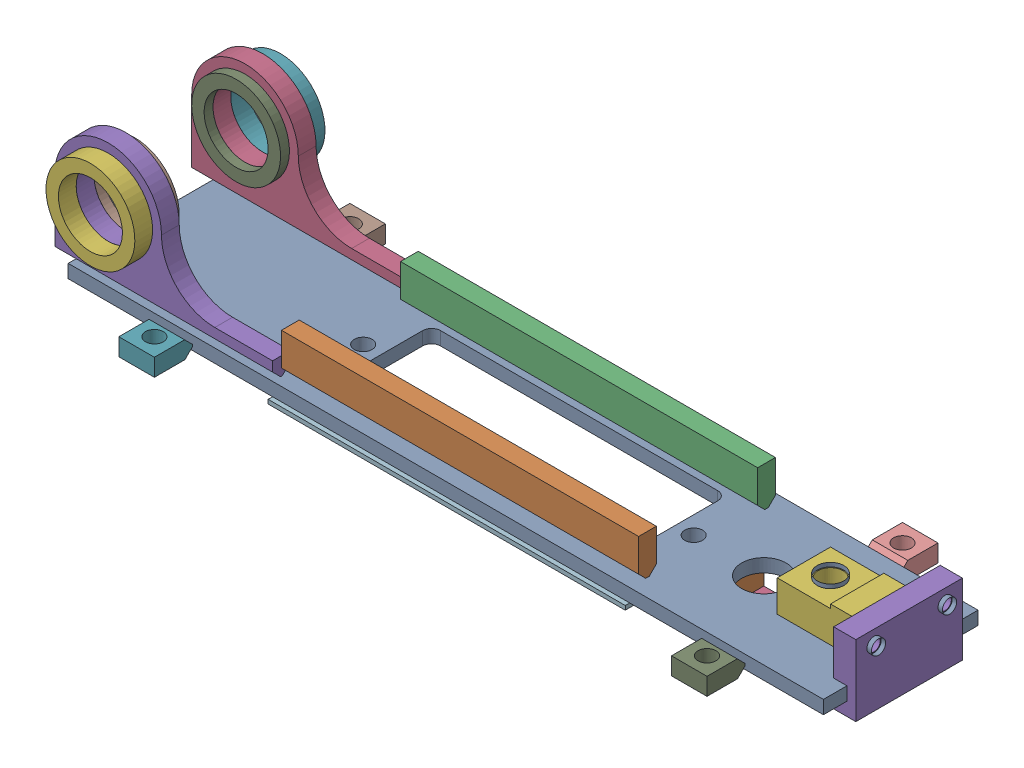
SolidWorks assembly g1_3_1_1_6, configuration 默认. Lengths in mm.
Overall size (880 200 260).
23 component instances, 19 part files, 0 mates.
Components (placement in the parent):
- g1_3_1_1_6-4_af0-1: g1_3_1_1_6-4_af0 [默认] at origin size (850 15 174)
- g1_3_1_1_6-8-1: g1_3_1_1_6-8 [默认] at (0 40 57) x (1 0 0) z (0 -1 0) size (402 20 44.8)
- g1_3_1_1_6-8-2: g1_3_1_1_6-8 [默认] at (0 40 -77) x (1 0 0) z (0 -1 0) size (402 20 44.8)
- g1_3_1_1_6-1-1: g1_3_1_1_6-1 [默认] at (-386 95 -87) x (1 0 0) z (0 -1 0) size (245 20 140)
- g1_3_1_1_6-1-2: g1_3_1_1_6-1 [默认] at (-386 95 67) x (1 0 0) z (0 -1 0) size (245 20 140)
- g1_3_1_1_6-3-1: g1_3_1_1_6-3 [默认] at (-386 95 87) x (-1 0 0) z (0 1 0) size (100 20 100)
- g1_3_1_1_6-3-2: g1_3_1_1_6-3 [默认] at (-386 95 -107) x (-1 0 0) z (0 1 0) size (100 20 100)
- g1_3_1_1_6-2-1: g1_3_1_1_6-2 [默认] at (-386 95 57) x (-1 0 0) z (0 1 0) size (100 10 100)
- g1_3_1_1_6-2-2: g1_3_1_1_6-2 [默认] at (-386 95 -57) x (1 0 0) z (0 1 0) size (100 10 100)
- g1_3_1_1_6-6_af1-1: g1_3_1_1_6-6_af1 [默认] at (186 -5 0) x (0 0 -1) z (1 0 0) size (130 4.6 30)
- g1_3_1_1_6-6_af0-1: g1_3_1_1_6-6_af0 [默认] at (-186 -5 0) x (0 0 -1) z (1 0 0) size (130 4.6 30)
- g1_3_1_1_6-7_af0-1: g1_3_1_1_6-7_af0 [默认] at (0 0 78.5) x (1 0 0) z (0 0 -1) size (402 4.6 27)
- g1_3_1_1_6-7_af1-1: g1_3_1_1_6-7_af1 [默认] at (0 -5 -78.5) size (402 4.6 27)
- g1_3_1_1_6-9-1: g1_3_1_1_6-9 [默认] at (220 -17 0) x (0 1 0) z (0 0 -1) size (35 15 60)
- g1_3_1_1_6-9_af0-1: g1_3_1_1_6-9_af0 [默认] at (310 -17 0) x (0 1 0) z (0 0 1) size (35 15 60)
- g1_3_1_1_6-10-1: g1_3_1_1_6-10 [默认] at (265 -45 0) size (60 20 60)
- g1_3_1_1_6-12_af0-1: g1_3_1_1_6-12_af0 [默认] at (434 25 0.5) x (0 0 1) z (0 -1 0) size (120 25 80)
- g1_3_1_1_6-11_af0-1: g1_3_1_1_6-11_af0 [默认] at (357 15 0) size (94 40 60)
- g1_3_1_1_6-5_af0-1: g1_3_1_1_6-5_af0 [默认] at (-311 -5 108.5) x (0 0 -1) z (1 0 0) size (43 19.6 40)
- g1_3_1_1_6-5_af1-1: g1_3_1_1_6-5_af1 [默认] at (-311 -5 -108.5) x (0 0 1) z (-1 0 0) size (43 19.6 40)
- g1_3_1_1_6-5_af2-1: g1_3_1_1_6-5_af2 [默认] at (311 -5 108.5) x (0 0 -1) z (1 0 0) size (43 19.6 40)
- g1_3_1_1_6-5_af3-1: g1_3_1_1_6-5_af3 [默认] at (311 -5 -108.5) x (0 0 1) z (-1 0 0) size (43 19.6 40)
- g1_3_1_1_6_more-1: g1_3_1_1_6_more [默认] at origin size (109 70.2 96)
